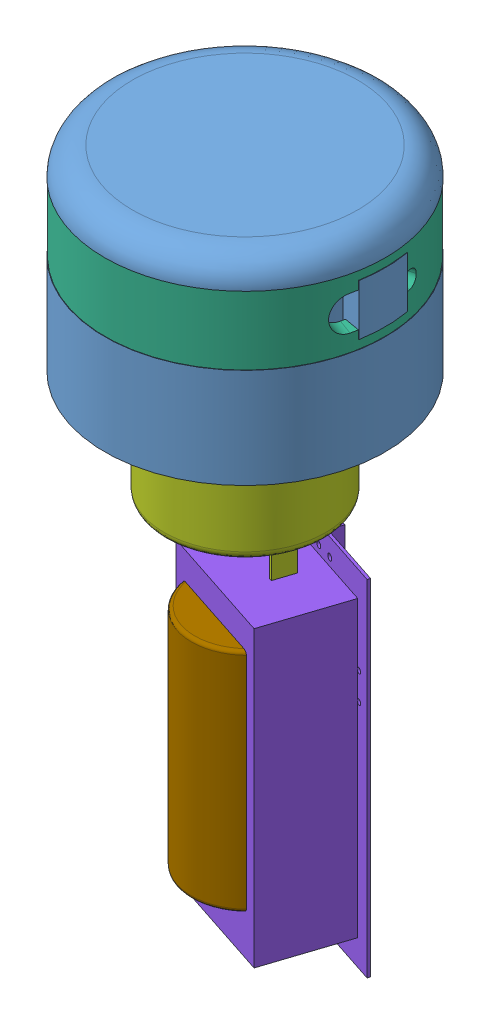
SolidWorks assembly Top Level Assembly, configuration Default. Lengths in mm.
Overall size (49.24 101.93 49.24).
22 component instances, 9 part files, 14 mates.
Components (placement in the parent):
- Inner-1: Inner [Default] at (-30.686 10.4087 12.7276) size (41.28 28.83 41.27)
- Retaining Ring-1: Retaining Ring [Default] at (-30.686 15.5776 12.7276) size (33.4 3.17 33.4)
- Pump Assy-1: Pump Assy [Default] at (-30.686 4.4651 12.7276) x (-0.912005 0 0.41018) z (-0.41018 0 -0.912005) size (41.82 14.61 41.82)
  - Wheel-1: Wheel [Default] at origin size (25.4 4 25.4)
  - Roller Assembly-1: Roller Assembly [Default] at (-10.3187 6.35 0) x (0.813985 0 0.580886) z (-0.580886 0 0.813985) size (16.81 12.7 16.81)
    - dowel-1: dowel [Default] at origin size (3.17 12.7 3.17)
    - Sleeve Bearing-1: Sleeve Bearing [Default] x (0.980576 0 0.196139) z (-0.196139 0 0.980576) size (14.29 6.35 14.29)
  - Roller Assembly-2: Roller Assembly [Default] at (0 6.35 -10.3187) x (-0.580886 0 0.813985) z (-0.813985 0 -0.580886) size (16.81 12.7 16.81)
    - dowel-1: dowel [Default] at origin size (3.17 12.7 3.17)
    - Sleeve Bearing-1: Sleeve Bearing [Default] x (0.980576 0 0.196139) z (-0.196139 0 0.980576) size (14.29 6.35 14.29)
  - Roller Assembly-3: Roller Assembly [Default] at (10.3187 6.35 0) x (-0.813985 0 -0.580886) z (0.580886 0 -0.813985) size (16.81 12.7 16.81)
    - dowel-1: dowel [Default] at origin size (3.17 12.7 3.17)
    - Sleeve Bearing-1: Sleeve Bearing [Default] x (0.980576 0 0.196139) z (-0.196139 0 0.980576) size (14.29 6.35 14.29)
  - Roller Assembly-4: Roller Assembly [Default] at (0 6.35 10.3187) x (0.580886 0 -0.813985) z (0.813985 0 0.580886) size (16.81 12.7 16.81)
    - dowel-1: dowel [Default] at origin size (3.17 12.7 3.17)
    - Sleeve Bearing-1: Sleeve Bearing [Default] x (0.980576 0 0.196139) z (-0.196139 0 0.980576) size (14.29 6.35 14.29)
  - Wheel-2: Wheel [Default] at (0 12.7 0) x (-1 0 0) z (0 0 1) size (25.4 4 25.4)
- Retaining Ring-2: Retaining Ring [Default] at (-30.686 6.0526 12.7276) x (0.953252 0 -0.302175) z (0.302175 0 0.953252) size (33.4 3.17 33.4)
- Outer-1: Outer [Default] at (-30.686 10.408 12.7276) size (41.15 10.08 41.15)
- Motor-1: Motor [Default] at (-30.686 -25.2275 12.7276) x (-0.950081 0 -0.312004) z (0.312004 0 -0.950081) size (23.75 40.04 23.75)
- DTM17E0000-1: DTM17E0000 [Default] at (-38.5479 -82.4145 0.6443) x (0 1 0) z (0.312004 0 -0.950081) size (50.8 22.37 16.38)
- Battery-1: Battery [Default] at (-30.7037 -72.7836 12.3421) size (16.51 33.99 16.51)
Mates (geometry in assembly coordinates):
- Coincident1: coincident anti-aligned: plane of Inner-1 through (-47.196 17.1651 12.7276) normal (0 -1 0); plane of Retaining Ring-1 through (-47.3865 17.1651 12.7276) normal (0 1 0)
- Concentric1: concentric aligned: cylinder of Inner-1 through (-30.686 10.4087 12.7276) axis (0 -1 0) radius 16.51; cylinder of Retaining Ring-1 through (-30.686 15.5776 12.7276) axis (0 -1 0) radius 16.7005
- Concentric2: concentric anti-aligned: cylinder of Inner-1 through (-30.686 10.4087 12.7276) axis (0 -1 0) radius 16.51; cylinder of Pump Assy-1/Wheel-2 through (-30.686 14.8791 12.7276) axis (0 1 0) radius 12.7
- Coincident2: coincident anti-aligned: plane of Retaining Ring-1 through (-47.3865 13.9901 12.7276) normal (0 -1 0); plane of Pump Assy-1/Roller Assembly-2/Sleeve Bearing-1 through (-28.8945 13.9901 28.0004) normal (0 1 0)
- Concentric3: concentric aligned: cylinder of Inner-1 through (-30.686 10.4087 12.7276) axis (0 -1 0) radius 16.51; cylinder of Retaining Ring-2 through (-30.686 6.0526 12.7276) axis (0 -1 0) radius 16.7005
- Coincident3: coincident anti-aligned: plane of Pump Assy-1/Roller Assembly-1/Sleeve Bearing-1 through (-15.4132 7.6401 10.9362) normal (0 -1 0); plane of Retaining Ring-2 through (-46.6058 7.6401 17.7741) normal (0 1 0)
- Concentric4: concentric aligned: cylinder of Inner-1 through (-30.686 10.4087 12.7276) axis (0 -1 0) radius 17.78; cylinder of Outer-1 through (-30.686 10.408 12.7276) axis (0 -1 0) radius 20.574
- Coincident8: coincident anti-aligned: plane of Inner-1 through (-48.466 5.3661 12.7276) normal (0 1 0); plane of Outer-1 through (-51.26 5.3661 12.7276) normal (0 -1 0)
- Coincident9: coincident anti-aligned: plane of Inner-1 through (-30.686 10.4087 12.7276) normal (-0.173648 0 -0.984808); plane of Outer-1 through (-30.686 10.408 12.7276) normal (0.173648 0 0.984808)
- Concentric5: concentric aligned: cylinder of Pump Assy-1/Wheel-1 through (-30.686 6.7511 12.7276) axis (0 -1 0) radius 1.4986; cylinder of Motor-1 through (-30.686 10.2436 12.7276) axis (0 -1 0) radius 0.9906
- Coincident10: coincident anti-aligned: plane of Pump Assy-1/Wheel-1 through (-30.686 3.5126 12.7276) normal (0 -1 0); plane of Motor-1 through (-30.686 3.5126 12.7276) normal (0 1 0)
- Distance1: distance = 10.16 mm anti-aligned: plane of Motor-1 through (-30.686 -25.2275 12.7276) normal (0 -1 0); plane of DTM17E0000-1 through (-23.2634 -35.3875 18.822) normal (0 1 0)
- Tangent4: tangent anti-aligned: plane of DTM17E0000-1 through (-38.6763 -82.4145 1.0352) normal (-0.312004 0 0.950081); cylinder of Battery-1 through (-30.7037 -39.408 12.3421) axis (0 -1 0) radius 8.255
- Coincident12: coincident aligned: plane of Motor-1 through (-38.8377 -29.7995 8.4465) normal (-0.950081 0 -0.312004); plane of DTM17E0000-1 through (-40.3972 -35.3875 13.1953) normal (-0.950081 0 -0.312004)
